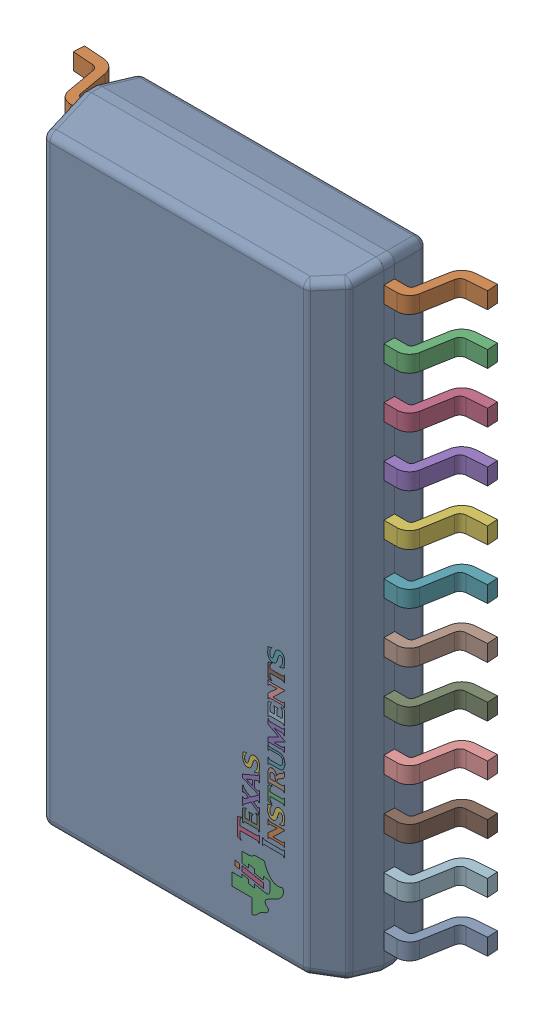
SolidWorks assembly U5, configuration Défaut. Lengths in mm.
Overall size (10.34 15.4 2.65).
28 component instances, 4 part files, 0 mates.
Components (placement in the parent):
- IC_Texas_Instruments_CD74HC4067M96_eec-1: IC_Texas_Instruments_CD74HC4067M96_eec [Défaut] at (-0.127 28.575 0) x (1 0 0) z (0 0 1) size (10.34 15.4 2.65)
  - BODY-SO-1: BODY-SO [Défaut] at (0 0 1.0825) x (0 1 0) z (1 0 0) size (15.4 2.45 7.5)
  - LEAD-SO-1: LEAD-SO [Défaut] at (4.315 6.985 0.25) x (0 1 0) z (1 0 0) size (0.41 1.43 1.42)
  - LEAD-SO-2: LEAD-SO [Défaut] at (4.315 5.715 0.25) x (0 1 0) z (1 0 0) size (0.41 1.43 1.42)
  - LEAD-SO-3: LEAD-SO [Défaut] at (4.315 4.445 0.25) x (0 1 0) z (1 0 0) size (0.41 1.43 1.42)
  - LEAD-SO-4: LEAD-SO [Défaut] at (4.315 3.175 0.25) x (0 1 0) z (1 0 0) size (0.41 1.43 1.42)
  - LEAD-SO-5: LEAD-SO [Défaut] at (4.315 1.905 0.25) x (0 1 0) z (1 0 0) size (0.41 1.43 1.42)
  - LEAD-SO-6: LEAD-SO [Défaut] at (4.315 0.635 0.25) x (0 1 0) z (1 0 0) size (0.41 1.43 1.42)
  - LEAD-SO-7: LEAD-SO [Défaut] at (4.315 -0.635 0.25) x (0 1 0) z (1 0 0) size (0.41 1.43 1.42)
  - LEAD-SO-8: LEAD-SO [Défaut] at (4.315 -1.905 0.25) x (0 1 0) z (1 0 0) size (0.41 1.43 1.42)
  - LEAD-SO-9: LEAD-SO [Défaut] at (4.315 -3.175 0.25) x (0 1 0) z (1 0 0) size (0.41 1.43 1.42)
  - LEAD-SO-10: LEAD-SO [Défaut] at (4.315 -4.445 0.25) x (0 1 0) z (1 0 0) size (0.41 1.43 1.42)
  - LEAD-SO-11: LEAD-SO [Défaut] at (4.315 -5.715 0.25) x (0 1 0) z (1 0 0) size (0.41 1.43 1.42)
  - LEAD-SO-12: LEAD-SO [Défaut] at (4.315 -6.985 0.25) x (0 1 0) z (1 0 0) size (0.41 1.43 1.42)
  - LEAD-SO-13: LEAD-SO [Défaut] at (-4.315 6.985 0.25) x (0 -1 0) z (-1 0 0) size (0.41 1.43 1.42)
  - LEAD-SO-14: LEAD-SO [Défaut] at (-4.315 5.715 0.25) x (0 -1 0) z (-1 0 0) size (0.41 1.43 1.42)
  - LEAD-SO-15: LEAD-SO [Défaut] at (-4.315 4.445 0.25) x (0 -1 0) z (-1 0 0) size (0.41 1.43 1.42)
  - LEAD-SO-16: LEAD-SO [Défaut] at (-4.315 3.175 0.25) x (0 -1 0) z (-1 0 0) size (0.41 1.43 1.42)
  - LEAD-SO-17: LEAD-SO [Défaut] at (-4.315 1.905 0.25) x (0 -1 0) z (-1 0 0) size (0.41 1.43 1.42)
  - LEAD-SO-18: LEAD-SO [Défaut] at (-4.315 0.635 0.25) x (0 -1 0) z (-1 0 0) size (0.41 1.43 1.42)
  - LEAD-SO-19: LEAD-SO [Défaut] at (-4.315 -0.635 0.25) x (0 -1 0) z (-1 0 0) size (0.41 1.43 1.42)
  - LEAD-SO-20: LEAD-SO [Défaut] at (-4.315 -1.905 0.25) x (0 -1 0) z (-1 0 0) size (0.41 1.43 1.42)
  - LEAD-SO-21: LEAD-SO [Défaut] at (-4.315 -3.175 0.25) x (0 -1 0) z (-1 0 0) size (0.41 1.43 1.42)
  - LEAD-SO-22: LEAD-SO [Défaut] at (-4.315 -4.445 0.25) x (0 -1 0) z (-1 0 0) size (0.41 1.43 1.42)
  - LEAD-SO-23: LEAD-SO [Défaut] at (-4.315 -5.715 0.25) x (0 -1 0) z (-1 0 0) size (0.41 1.43 1.42)
  - LEAD-SO-24: LEAD-SO [Défaut] at (-4.315 -6.985 0.25) x (0 -1 0) z (-1 0 0) size (0.41 1.43 1.42)
  - Texas Logo Yury-1: Texas Logo Yury [Défaut] at (2.174 -7.1221 2.551) x (0 1 0) z (0 0 1) size (1.32 1.29 0.11)
  - Texas Logo Yury - Copy-1: Texas Logo Yury - Copy [Défaut] at (2.0641 -7.1534 2.551) x (0 1 0) z (0 0 1) size (4.61 1.2 0.1)
